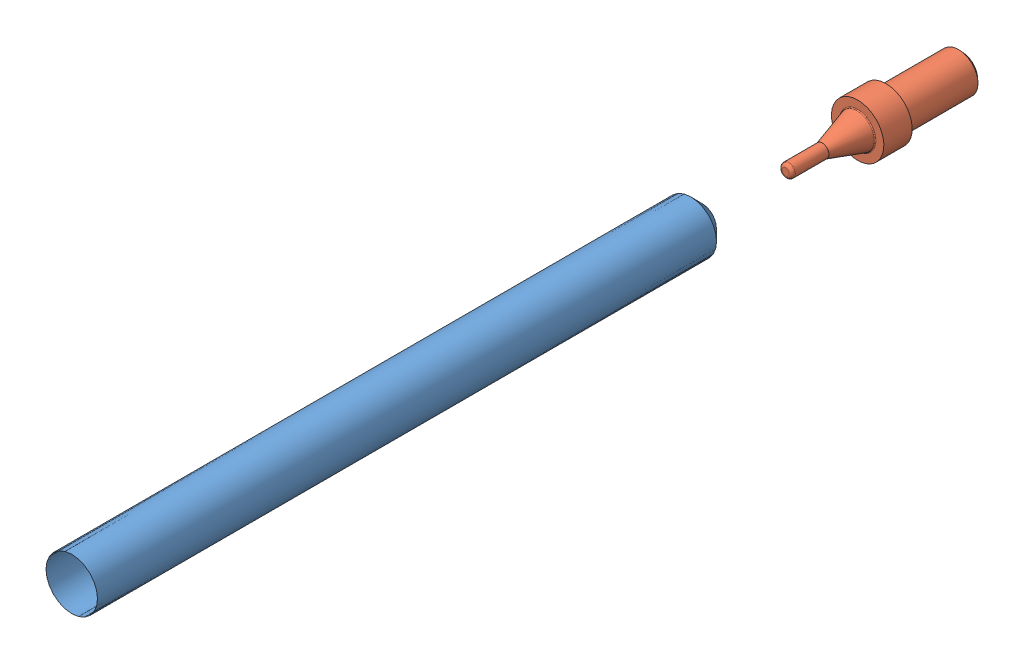
SolidWorks assembly drift and base, configuration Default. Lengths in mm.
Overall size (14.85 14.85 215.17).
2 component instances, 2 part files, 1 mates.
Components (placement in the parent):
- nozzle drift-1: nozzle drift [Default] at (-60.5995 19.9818 -57.7988) size (12.44 12.44 152.4)
- base-1: base [Default] at (-60.5995 19.9818 -77.8801) x (0.191463 0.9815 0) z (0 0 -1) size (12.66 12.66 42.69)
Mates (geometry in assembly coordinates):
- Concentric1: concentric aligned: cylinder of nozzle drift-1 through (-60.5995 19.9818 94.6012) axis (0 0 -1) radius 1.8; cylinder of base-1 through (-60.5995 19.9818 -10.2351) axis (0 0 -1) radius 1.6
